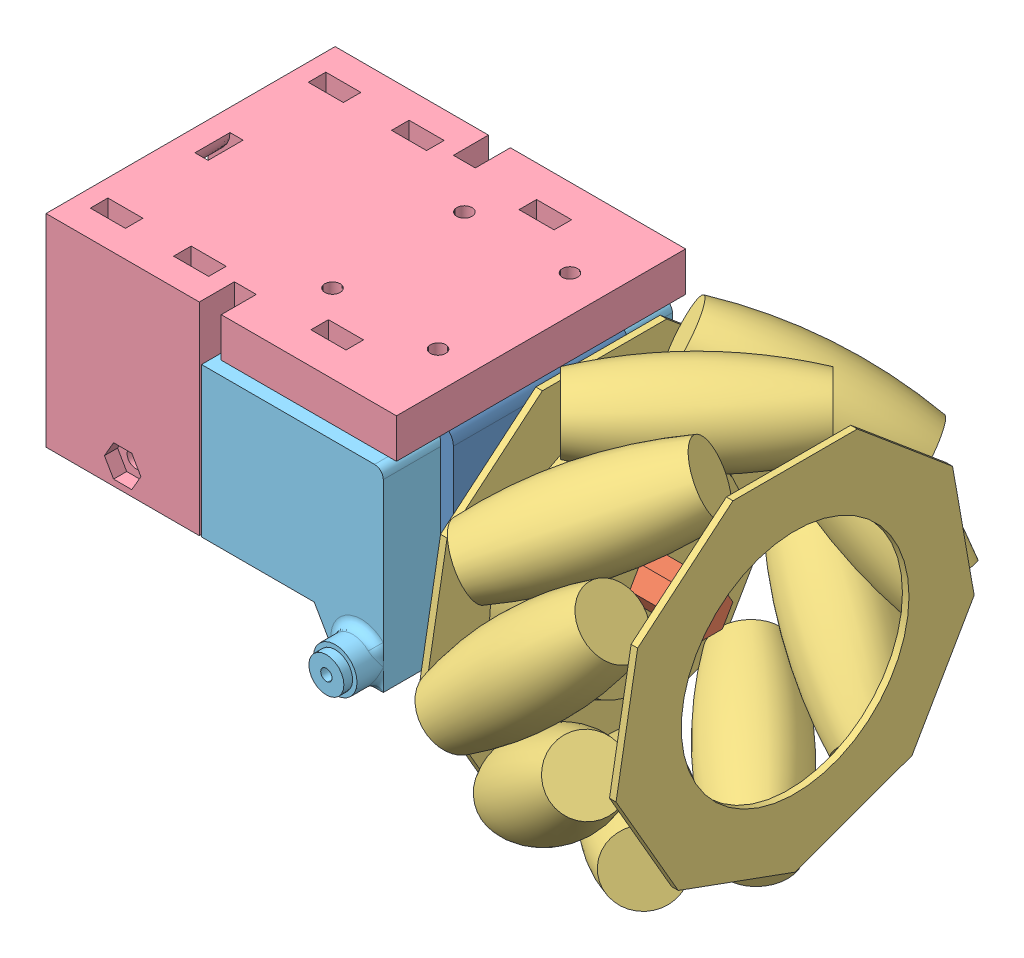
SolidWorks assembly motor base assy, configuration Default. Lengths in mm.
Overall size (138 96.31 96.18).
6 component instances, 6 part files, 17 mates.
Components (placement in the parent):
- motor_bracket-1: motor_bracket [Default] at origin size (42.8 47.2 40)
- motor-1: motor [Default] at (-84 0 0) x (1 0 0) z (0 1 0) size (122 56 32.5) (hidden)
- wheel_adapter-1: wheel_adapter [Default] at (20 0 0) x (1 0 0) z (0 -0.866025 0.5) size (33 10 10)
- wheel-1: wheel [Default] at (38.5 0 0) x (0 0 -1) z (1 0 0) size (96.18 96.31 45)
- motor_bracket_top-1: motor_bracket_top [Default] at (0 27.2 0) x (1 0 0) z (0 1 0) size (80 66 46.2)
- motor_bracket_bottom-1: motor_bracket_bottom [Default] x (0 0 1) z (-1 0 0) size (82 44.1 41.5)
Mates (geometry in assembly coordinates):
- Concentric1: concentric aligned: cylinder of motor_bracket-1 through (3 0 0) axis (-1 0 0) radius 10; cylinder of motor-1 through (3 0 0) axis (-1 0 0) radius 10
- Coincident1: coincident anti-aligned: plane of motor_bracket-1 through (0 0 0) normal (-1 0 0); plane of motor-1 through (0 0 0) normal (1 0 0)
- Parallel1: parallel anti-aligned: plane of motor_bracket-1 through (-39.8 24.2 20) normal (0 -1 0); plane of motor-1 through (-102 16.25 0) normal (0 1 0)
- Concentric2: concentric anti-aligned: cylinder of motor-1 through (20 0 0) axis (-1 0 0) radius 3; cylinder of wheel_adapter-1 through (9 0 0) axis (1 0 0) radius 5
- Coincident3: coincident anti-aligned: plane of motor-1 through (20 0 0) normal (1 0 0); plane of wheel_adapter-1 through (20 0 0) normal (-1 0 0)
- Parallel2: parallel aligned: plane of motor_bracket-1 through (3 27.2 0) normal (0 1 0); plane of wheel_adapter-1 through (42 4.15 -2.396) normal (0 1 0)
- Concentric3: concentric aligned: cylinder of wheel_adapter-1 through (9 0 0) axis (1 0 0) radius 5; cylinder of wheel-1 through (20 0 0) axis (1 0 0) radius 6.4
- Parallel3: parallel aligned: plane of motor_bracket-1 through (3 27.2 0) normal (0 1 0); plane of wheel-1 through (38.5 -48 0) normal (0 1 0)
- Coincident6: coincident anti-aligned: plane of wheel_adapter-1 through (20 0 0) normal (1 0 0); plane of wheel-1 through (20 0 0) normal (-1 0 0)
- InPlace1: in place: plane of motor_bracket-1 through (3 27.2 0) normal (0 1 0); plane of motor_bracket_top-1 through (0 27.2 0) normal (0 1 0); moOrthogonalPlaneRef_w of motor_bracket-1 through (3 27.2 0) normal (0 1 0); plane of motor_bracket_top-1 through (0 27.2 0) normal (0 0 -1); plane of motor_bracket-1 through (3 27.2 0) normal (0 1 0); plane of motor_bracket_top-1 through (0 27.2 0) normal (1 0 0); plane of motor_bracket-1 through (3 27.2 0) normal (0 1 0); unknown of motor_bracket_top-1
- Coincident7: coincident aligned: plane of motor_bracket-1; plane of motor_bracket_top-1
- Coincident8: coincident aligned: moOrthogonalPlaneRef_w of motor_bracket-1 through (0 27.2 0) normal (0 0 -1); plane of motor_bracket_top-1 through (0 27.2 0) normal (0 0 -1)
- Coincident9: coincident anti-aligned: moOrthogonalPlaneRef_w of motor_bracket-1 through (0 27.2 0) normal (-1 0 0); plane of motor_bracket_top-1 through (0 27.2 0) normal (1 0 0)
- InPlace2: in place: plane of motor_bracket-1 through (0 0 0) normal (-1 0 0); plane of motor_bracket_bottom-1 through (0 0 0) normal (-1 0 0); plane of motor_bracket-1 through (0 0 0) normal (-1 0 0); plane of motor_bracket_bottom-1 through (0 0 0) normal (0 1 0); plane of motor_bracket-1 through (0 0 0) normal (-1 0 0); plane of motor_bracket_bottom-1 through (0 0 0) normal (0 0 1); plane of motor_bracket-1 through (0 0 0) normal (-1 0 0); unknown of motor_bracket_bottom-1
- Coincident7: coincident aligned: plane of motor_bracket-1; plane of motor_bracket_bottom-1
- Coincident8: coincident aligned: moOrthogonalPlaneRef_w of motor_bracket-1 through (0 0 0) normal (0 1 0); plane of motor_bracket_bottom-1 through (0 0 0) normal (0 1 0)
- Coincident9: coincident anti-aligned: moOrthogonalPlaneRef_w of motor_bracket-1 through (0 0 0) normal (0 0 -1); plane of motor_bracket_bottom-1 through (0 0 0) normal (0 0 1)
